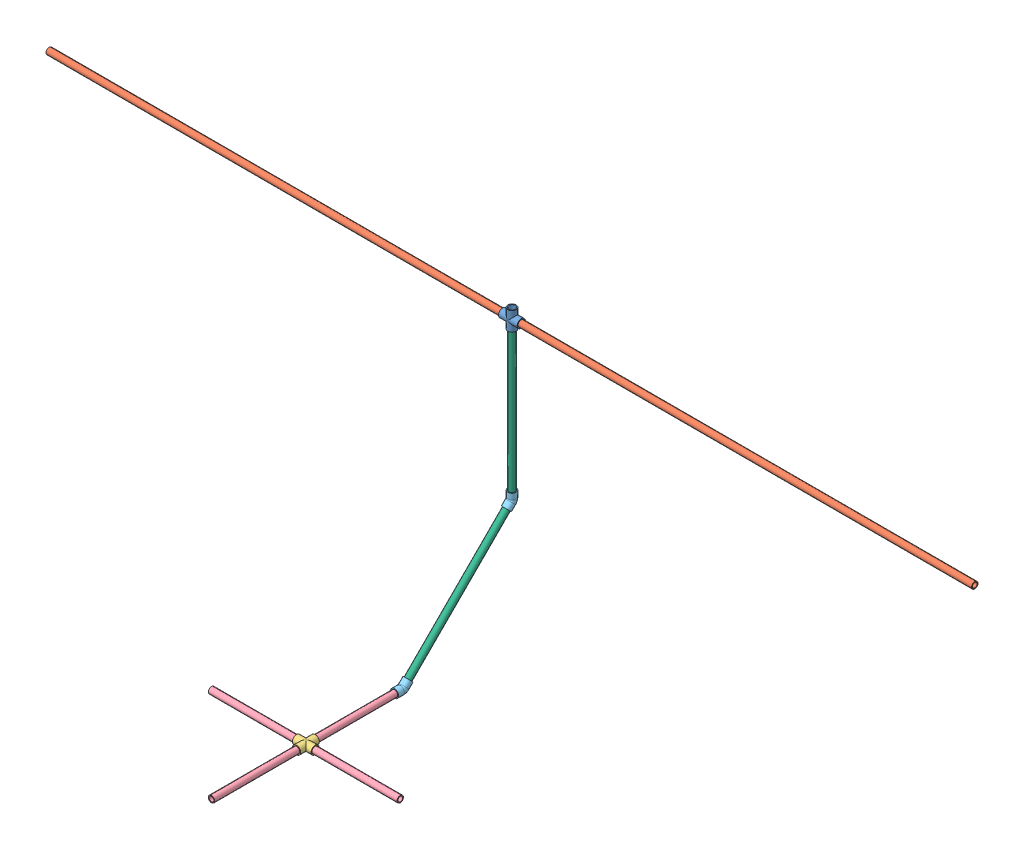
SolidWorks assembly LOWER DEPTH MARKER, configuration Default. Lengths in mm.
Overall size (3074.99 929.57 1028.09).
12 component instances, 6 part files, 25 mates.
Components (placement in the parent):
- 1-2 PVC CROSS YELLOW-1: 1-2 PVC CROSS YELLOW [4880K241] at (21.0763 31.6776 49.0256) size (61.91 61.91 27.56)
- 1-2 PVC PIPE 47CM YELLOW-1: 1-2 PVC PIPE 47CM YELLOW [48925K91] at (-754.4174 31.6776 49.0256) x (0 0 -1) z (1 0 0) size (21.34 21.34 1524)
- 1-2 PVC PIPE 47CM YELLOW-2: 1-2 PVC PIPE 47CM YELLOW [48925K91] at (796.5701 31.6776 49.0256) x (0 0 1) z (-1 0 0) size (21.34 21.34 1524)
- 1-2 PVC CROSS-1: 1-2 PVC CROSS [4880K241] at (21.0763 -853.1526 733.8558) x (1 0 0) z (0 1 0) size (61.91 61.91 27.56)
- 1-2 PVC PIPE 30CM-1: 1-2 PVC PIPE 30CM [48925K91] at (-142.4174 -853.1526 733.8558) x (0 0 -1) z (1 0 0) size (21.34 21.34 300)
- 1-2 PVC PIPE 30CM-2: 1-2 PVC PIPE 30CM [48925K91] at (21.0763 -853.1526 570.3621) size (21.34 21.34 300)
- 1-2 PVC PIPE 30CM-3: 1-2 PVC PIPE 30CM [48925K91] at (184.5701 -853.1526 733.8558) x (0 0 1) z (-1 0 0) size (21.34 21.34 300)
- 1-2 PVC PIPE 30CM-4: 1-2 PVC PIPE 30CM [48925K91] at (21.0763 -853.1526 897.3496) x (1 0 0) z (0 0 -1) size (21.34 21.34 300)
- 1-2 PVC ELBOW 45-1: 1-2 PVC ELBOW 45 [4880K31] at (21.0763 -489.1821 49.0256) x (0 -0.707107 -0.707107) z (-1 0 0) size (42.09 54.79 27.43)
- 1-2 PVC ELBOW 45-2: 1-2 PVC ELBOW 45 [4880K31] at (21.0763 -853.1526 412.9961) x (0 -1 0) z (-1 0 0) size (42.09 54.79 27.43)
- 1-2 PVC PIPE 50CM-1: 1-2 PVC PIPE 50CM [48925K91] at (21.0763 -671.1674 231.0108) x (0.990327 0.098115 0.098115) z (0 -0.707107 0.707107) size (21.34 21.34 500)
- 1-2 PVC PIPE 50CM-2: 1-2 PVC PIPE 50CM [48925K91] at (21.0763 -231.8161 49.0256) x (0.923728 0 -0.383049) z (0 -1 0) size (21.34 21.34 500)
Mates (geometry in assembly coordinates):
- Coincident1: coincident anti-aligned: plane of 1-2 PVC CROSS YELLOW-1 through (34.5701 31.6776 49.0256) normal (1 0 0); plane of 1-2 PVC PIPE 47CM YELLOW-2 through (34.5701 31.6776 49.0256) normal (-1 0 0)
- Concentric1: concentric anti-aligned: cone of 1-2 PVC CROSS YELLOW-1 through (52.0326 31.6776 49.0256) axis (-1 0 0); cylinder of 1-2 PVC PIPE 47CM YELLOW-2 through (34.5701 31.6776 49.0256) axis (1 0 0) radius 10.668
- Coincident2: coincident anti-aligned: plane of 1-2 PVC CROSS YELLOW-1 through (7.5826 31.6776 49.0256) normal (-1 0 0); plane of 1-2 PVC PIPE 47CM YELLOW-1 through (7.5826 31.6776 49.0256) normal (1 0 0)
- Concentric2: concentric anti-aligned: cone of 1-2 PVC CROSS YELLOW-1 through (7.5826 31.6776 49.0256) axis (1 0 0); cylinder of 1-2 PVC PIPE 47CM YELLOW-1 through (7.5826 31.6776 49.0256) axis (-1 0 0) radius 10.668
- Coincident3: coincident anti-aligned: plane of 1-2 PVC CROSS-1 through (7.5826 -853.1526 733.8558) normal (-1 0 0); plane of 1-2 PVC PIPE 30CM-1 through (7.5826 -853.1526 733.8558) normal (1 0 0)
- Concentric3: concentric anti-aligned: cone of 1-2 PVC CROSS-1 through (7.5826 -853.1526 733.8558) axis (1 0 0); cylinder of 1-2 PVC PIPE 30CM-1 through (7.5826 -853.1526 733.8558) axis (-1 0 0) radius 10.668
- Coincident4: coincident anti-aligned: plane of 1-2 PVC CROSS-1 through (34.5701 -853.1526 733.8558) normal (1 0 0); plane of 1-2 PVC PIPE 30CM-3 through (34.5701 -853.1526 733.8558) normal (-1 0 0)
- Concentric4: concentric anti-aligned: cone of 1-2 PVC CROSS-1 through (52.0326 -853.1526 733.8558) axis (-1 0 0); cylinder of 1-2 PVC PIPE 30CM-3 through (34.5701 -853.1526 733.8558) axis (1 0 0) radius 10.668
- Coincident5: coincident anti-aligned: plane of 1-2 PVC CROSS-1 through (21.0763 -853.1526 747.3496) normal (0 0 1); plane of 1-2 PVC PIPE 30CM-4 through (21.0763 -853.1526 747.3496) normal (0 0 -1)
- Concentric5: concentric anti-aligned: cone of 1-2 PVC CROSS-1 through (21.0763 -853.1526 747.3496) axis (0 0 -1); cylinder of 1-2 PVC PIPE 30CM-4 through (21.0763 -853.1526 747.3496) axis (0 0 1) radius 10.668
- Coincident6: coincident anti-aligned: plane of 1-2 PVC CROSS-1 through (21.0763 -853.1526 720.3621) normal (0 0 -1); plane of 1-2 PVC PIPE 30CM-2 through (21.0763 -853.1526 720.3621) normal (0 0 1)
- Concentric6: concentric anti-aligned: cone of 1-2 PVC CROSS-1 through (21.0763 -853.1526 702.8996) axis (0 0 1); cylinder of 1-2 PVC PIPE 30CM-2 through (21.0763 -853.1526 720.3621) axis (0 0 -1) radius 10.668
- Coincident7: coincident anti-aligned: plane of 1-2 PVC PIPE 30CM-2 through (21.0763 -853.1526 420.3621) normal (0 0 -1); plane of 1-2 PVC ELBOW 45-2 through (21.0763 -853.1526 420.3621) normal (0 0 1)
- Concentric7: concentric aligned: cylinder of 1-2 PVC PIPE 30CM-2 through (21.0763 -853.1526 720.3621) axis (0 0 -1) radius 10.668; cone of 1-2 PVC ELBOW 45-2 through (21.0763 -853.1526 439.4121) axis (0 0 -1)
- Coincident8: coincident anti-aligned: plane of 1-2 PVC CROSS-1; plane of 1-2 PVC ELBOW 45-2 through (21.0763 -853.1526 412.9961) normal (-1 0 0)
- Coincident9: coincident aligned: plane of 1-2 PVC CROSS YELLOW-1 through (21.0763 31.6776 49.0256) normal (1 0 0); plane of 1-2 PVC CROSS-1
- Coincident10: coincident anti-aligned: plane of 1-2 PVC ELBOW 45-2 through (21.0763 -847.9441 407.7875) normal (0 0.707107 -0.707107); plane of 1-2 PVC PIPE 50CM-1 through (21.0763 -847.9441 407.7875) normal (0 -0.707107 0.707107)
- Concentric8: concentric anti-aligned: cone of 1-2 PVC ELBOW 45-2 through (21.0763 -847.9441 407.7875) axis (0 -0.707107 0.707107); cylinder of 1-2 PVC PIPE 50CM-1 through (21.0763 -847.9441 407.7875) axis (0 0.707107 -0.707107) radius 10.668
- Coincident11: coincident anti-aligned: plane of 1-2 PVC ELBOW 45-1 through (21.0763 -494.3907 54.2341) normal (0 -0.707107 0.707107); plane of 1-2 PVC PIPE 50CM-1 through (21.0763 -494.3907 54.2341) normal (0 0.707107 -0.707107)
- Concentric9: concentric aligned: cone of 1-2 PVC ELBOW 45-1 through (21.0763 -507.8611 67.7045) axis (0 0.707107 -0.707107); cylinder of 1-2 PVC PIPE 50CM-1 through (21.0763 -847.9441 407.7875) axis (0 0.707107 -0.707107) radius 10.668
- Coincident12: coincident aligned: plane of 1-2 PVC ELBOW 45-1 through (21.0763 -489.1821 49.0256) normal (-1 0 0); plane of 1-2 PVC ELBOW 45-2 through (21.0763 -853.1526 412.9961) normal (-1 0 0)
- Coincident13: coincident anti-aligned: plane of 1-2 PVC ELBOW 45-1 through (21.0763 -481.8161 49.0256) normal (0 1 0); plane of 1-2 PVC PIPE 50CM-2 through (21.0763 -481.8161 49.0256) normal (0 -1 0)
- Concentric10: concentric anti-aligned: cone of 1-2 PVC ELBOW 45-1 through (21.0763 -481.8161 49.0256) axis (0 -1 0); cylinder of 1-2 PVC PIPE 50CM-2 through (21.0763 -481.8161 49.0256) axis (0 1 0) radius 10.668
- Coincident14: coincident anti-aligned: plane of 1-2 PVC CROSS YELLOW-1 through (21.0763 18.1839 49.0256) normal (0 -1 0); plane of 1-2 PVC PIPE 50CM-2 through (21.0763 18.1839 49.0256) normal (0 1 0)
- Concentric11: concentric aligned: cone of 1-2 PVC CROSS YELLOW-1 through (21.0763 18.1839 49.0256) axis (0 1 0); cylinder of 1-2 PVC PIPE 50CM-2 through (21.0763 -481.8161 49.0256) axis (0 1 0) radius 10.668
